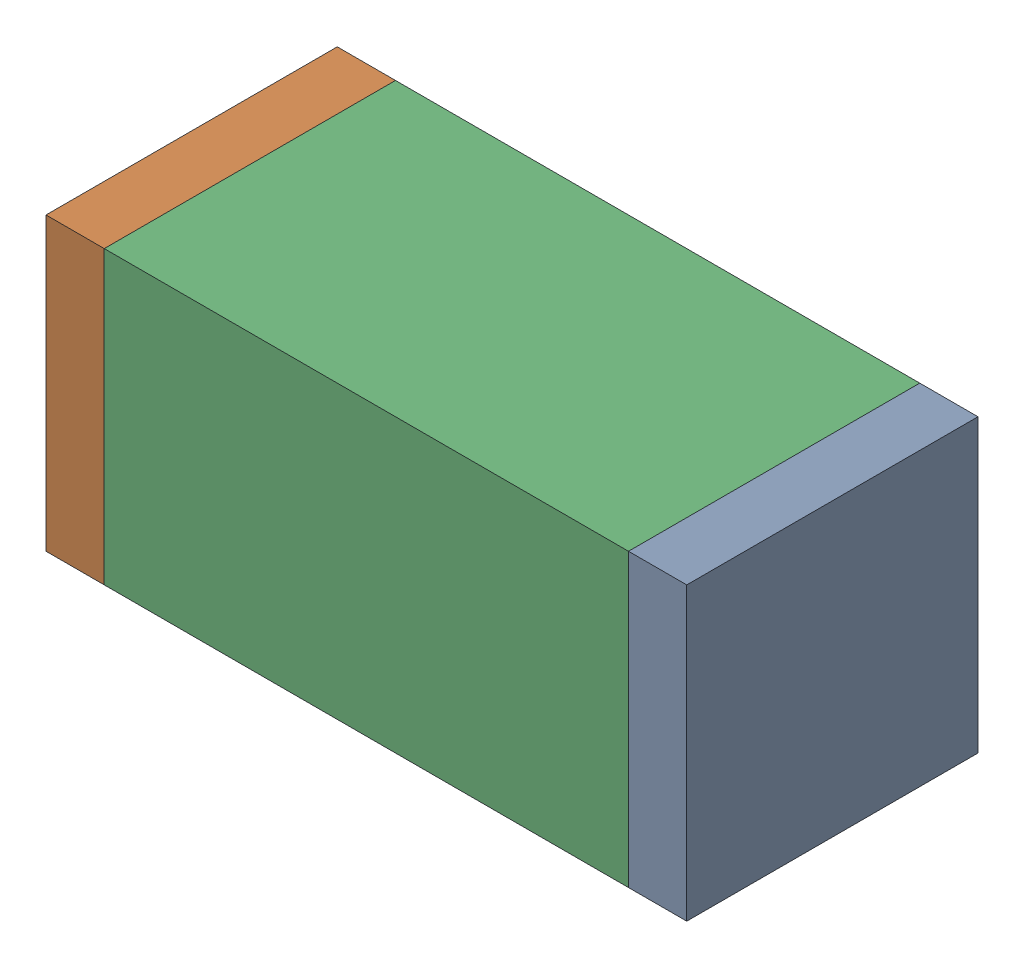
SolidWorks assembly C100, configuration Default. Lengths in mm.
Overall size (1.1 0.5 0.5).
6 component instances, 2 part files, 0 mates.
Components (placement in the parent):
- 810156080-1: 810156080 [Default] at (124.35 69.65 0) size (0.1 0.5 0.5)
  - Extruded_5-1: Extruded_5 [Default] at origin size (0.1 0.5 0.5)
- 810156080-2: 810156080 [Default] at (123.35 69.65 0) size (0.1 0.5 0.5)
  - Extruded_5-1: Extruded_5 [Default] at origin size (0.1 0.5 0.5)
- 836749680-1: 836749680 [Default] at (123.85 69.65 0) size (0.9 0.5 0.5)
  - Extruded_4-1: Extruded_4 [Default] at origin size (0.9 0.5 0.5)
